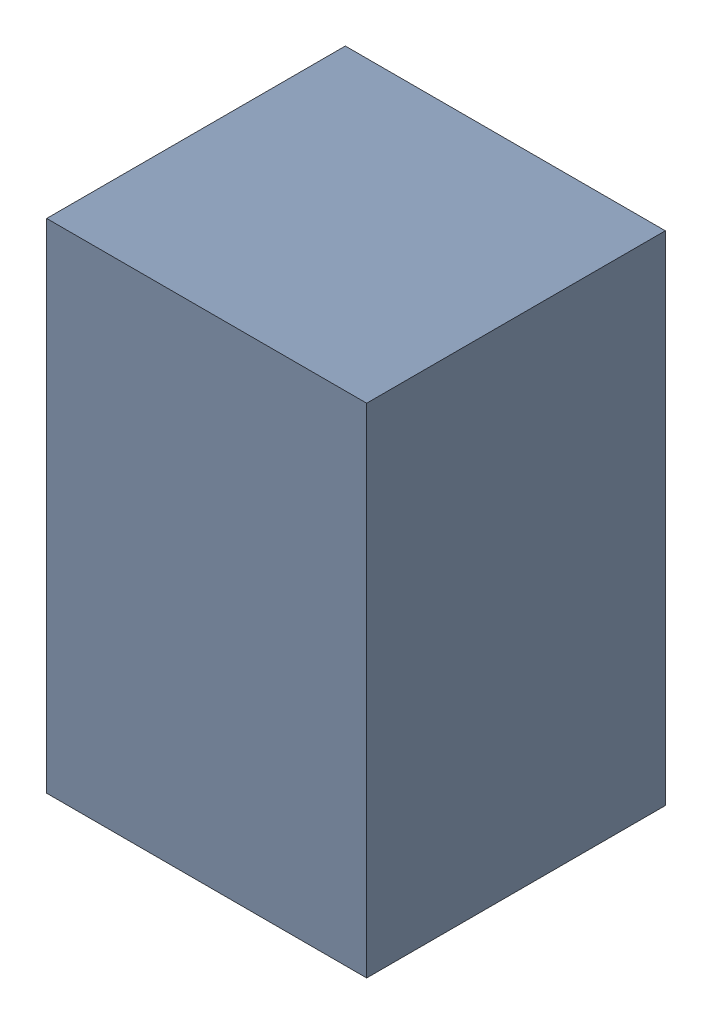
SolidWorks assembly CL2, configuration Default. Lengths in mm.
Overall size (1.35 2.1 1.26).
2 component instances, 1 part files, 0 mates.
Components (placement in the parent):
- 407985696-1: 407985696 [Default] at (30.988 48.2476 0.0127) size (1.35 2.1 1.26)
  - Extruded_1-1: Extruded_1 [Default] at origin size (1.35 2.1 1.26)
